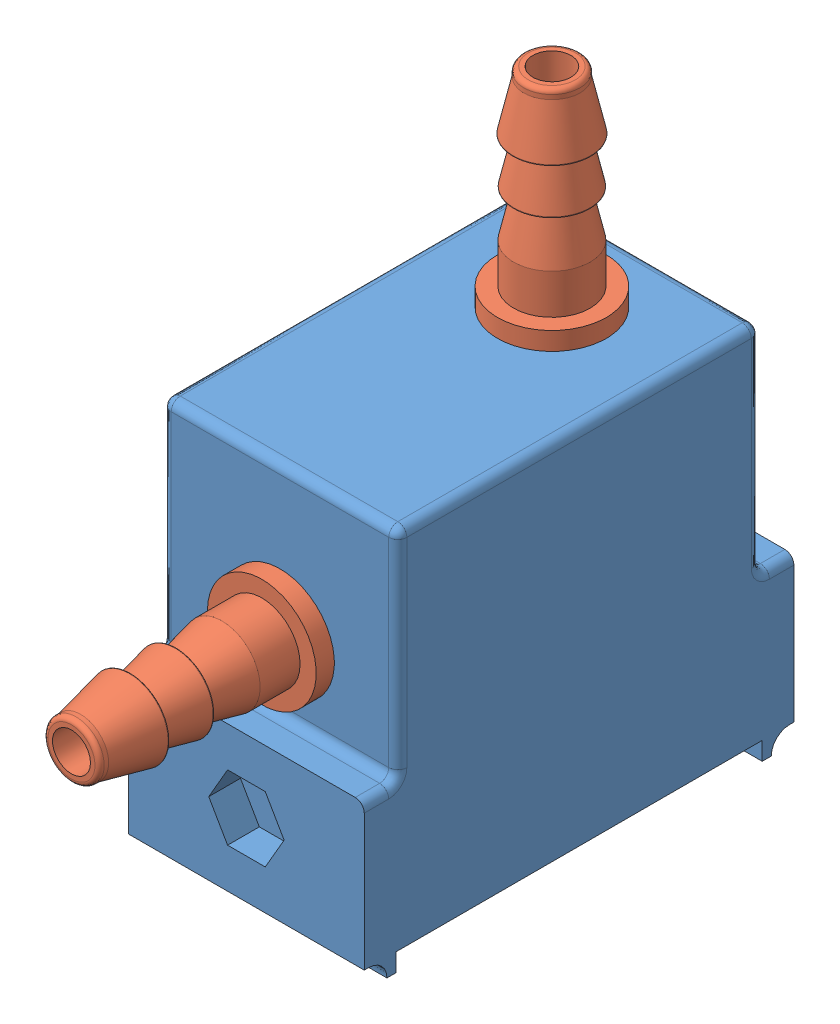
SolidWorks assembly Thermal Block Assembly, configuration Default. Lengths in mm.
Overall size (26 65 66.7).
6 component instances, 4 part files, 13 mates.
Components (placement in the parent):
- Thermal Block-1: Thermal Block [Default] at origin size (26 42 47.4)
- Gasket Material^Thermal Block Assembly-1: Gasket Material^Thermal Block Assembly [Default] at (-26.4925 0 -25.0102) (suppressed, hidden, virtual)
- M4 x 0.7 Hex Nut-3: M4 x 0.7 Hex Nut [90592A090] at (0 8 -21.8) x (-0.866025 0.5 0) z (-0.5 -0.866025 0) (suppressed, hidden)
- M4 x 0.7 Hex Nut-4: M4 x 0.7 Hex Nut [90592A090] at (0 8 21.8) x (0 1 0) z (1 0 0) (suppressed, hidden)
- Tube_Fitting_Final-1: Tube_Fitting_Final [Default] at (0 42 -10) x (0 1 0) z (1 0 0) size (23 12 12)
- Tube_Fitting_Final-2: Tube_Fitting_Final [Default] at (0 24 22) x (0 0 1) z (1 0 0) size (23 12 12)
Mates (geometry in assembly coordinates):
- Coincident5: coincident: plane of assembly; plane of Thermal Block-1 through (0 0 0) normal (0 -1 0); plane of Gasket Material^Thermal Block Assembly-1 through (-26.4925 0 -25.0102) normal (0 1 0)
- Coincident6: coincident aligned: line of Thermal Block-1 through (-13 0 -23.7) axis (0 0 1); line of Gasket Material^Thermal Block Assembly-1 through (-13 0 -20) axis (0 0 1)
- Distance1: distance = 3.7 mm aligned: plane of Gasket Material^Thermal Block Assembly-1 through (13 -1 -20) normal (0 0 -1); plane of Thermal Block-1 through (-13 16 -23.7) normal (0 0 -1)
- Concentric9: concentric aligned: circle of Thermal Block-1; circle of M4 x 0.7 Hex Nut-3
- Parallel3: parallel anti-aligned: plane of Thermal Block-1 through (2.0785 11.6 -20.2) normal (-0.866025 -0.5 0); plane of M4 x 0.7 Hex Nut-3 through (2.0207 11.5 -23.4) normal (0.866025 0.5 0)
- Coincident13: coincident anti-aligned: plane of Thermal Block-1 through (0 0 -20.2) normal (0 0 -1); plane of M4 x 0.7 Hex Nut-3 through (4.0415 8 -20.2) normal (0 0 1)
- Concentric10: concentric anti-aligned: circle of Thermal Block-1; circle of M4 x 0.7 Hex Nut-4
- Parallel4: parallel anti-aligned: plane of Thermal Block-1 through (-2.0785 4.4 20.2) normal (0.866025 0.5 0); plane of M4 x 0.7 Hex Nut-4 through (-4.0415 8 23.4) normal (-0.866025 -0.5 0)
- Coincident16: coincident anti-aligned: plane of Thermal Block-1 through (0 0 20.2) normal (0 0 1); plane of M4 x 0.7 Hex Nut-4 through (-2.0207 4.5 20.2) normal (0 0 -1)
- Concentric12: concentric anti-aligned: circle of Thermal Block-1; circle of Quarter_Fitting_Tight_V1_With_Support_0.2-1
- Coincident21: coincident anti-aligned: plane of Thermal Block-1 through (0 40 0) normal (0 1 0); plane of Quarter_Fitting_Tight_V1_With_Support_0.2-1 through (0 40 -10) normal (0 -1 0)
- Concentric13: concentric anti-aligned: circle of Thermal Block-1; circle of Quarter_Fitting_Tight_V1_With_Support_0.2-2
- Coincident22: coincident anti-aligned: plane of Thermal Block-1 through (-13 40 20) normal (0 0 1); plane of Quarter_Fitting_Tight_V1_With_Support_0.2-2 through (0 24 20) normal (0 0 -1)
